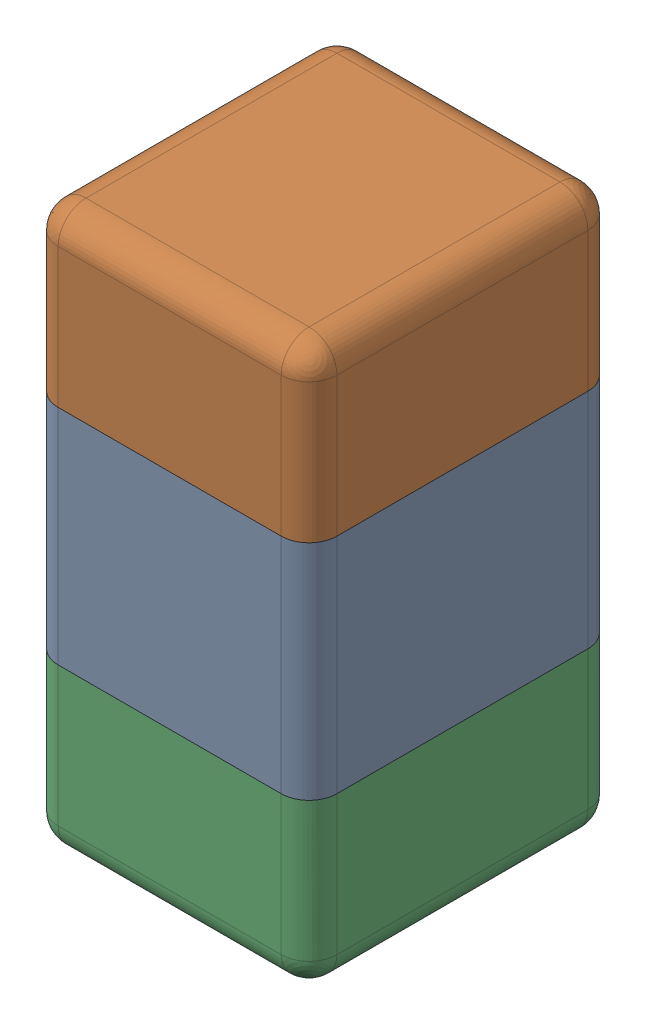
SolidWorks assembly C9, configuration Default. Lengths in mm.
Overall size (0.51 1.01 0.56).
5 component instances, 4 part files, 0 mates.
Components (placement in the parent):
- Cap_Kemet_C0402C562J5RACTU_eec-1: Cap_Kemet_C0402C562J5RACTU_eec [Default] at (145.5 90 -1.6914) x (0 -1 0) z (0 0 -1) size (1.01 0.51 0.56)
  - body_2-1: body_2 [Default] at origin size (0.4 0.5 0.55)
  - terminals-1: terminals [Default] at origin size (0.31 0.51 0.56)
  - terminals_2-1: terminals_2 [Default] at origin size (0.31 0.51 0.56)
  - value-1: value [Default] at (0 0 0.55) size (0.37 0.29 0.15)
